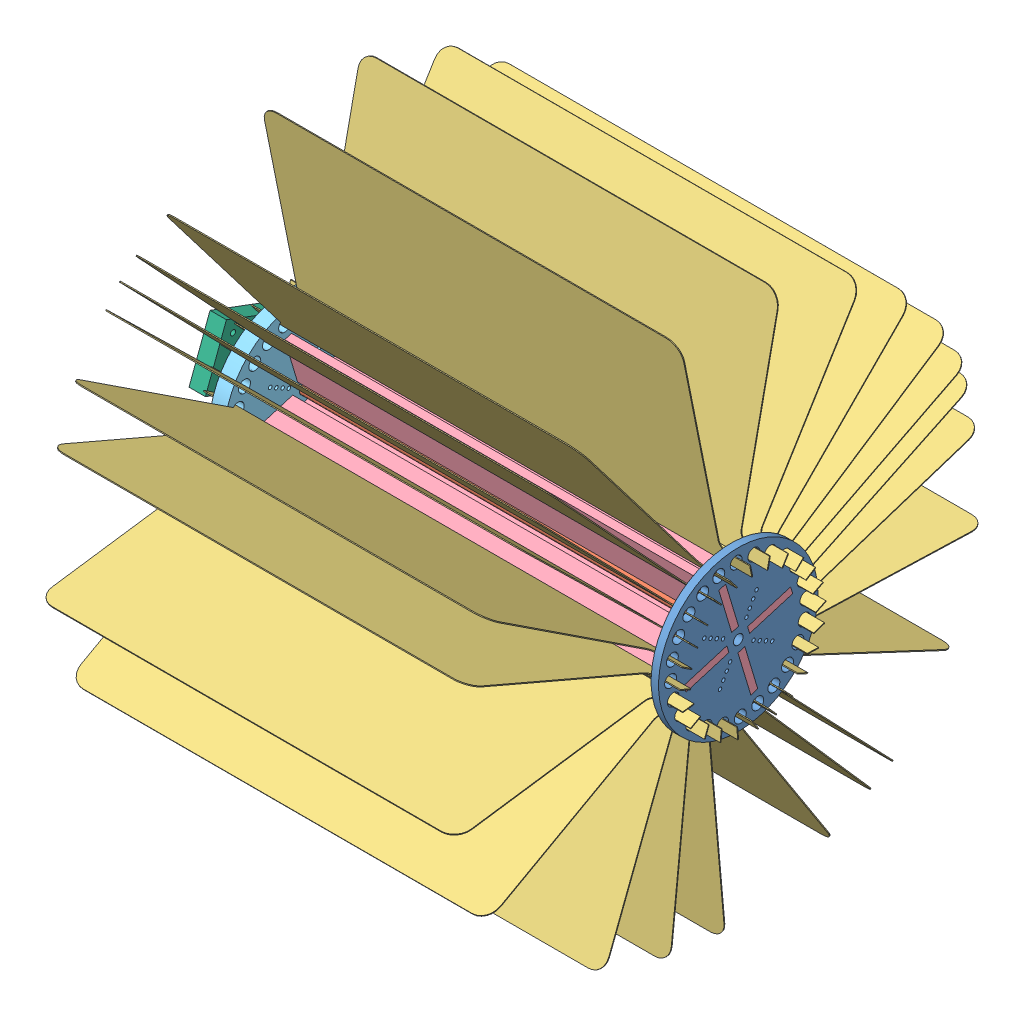
SolidWorks assembly FlipHubAssy_11_14_16, configuration Default. Lengths in mm.
32 component instances, 6 part files, 68 mates.
Components (placement in the parent):
- Hub_11_16_16v1-3: Hub_11_16_16v1 [Kerf Removed] at (92.075 0 0) x (0 0.287729 -0.957712) z (1 0 0) size (67.6 67.6 3.17)
- 4mmShaft-1: 4mmShaft [Default] at (-121.3698 0 0) x (0 0.397838 0.917456) z (1 0 0) size (4 4 201.85)
- flipcard-2: flipcard [Default] at (101.6 25.4911 6.9469) x (-1 0 0) z (0 -0.794345 -0.607467) size (203.2 0.36 88.9)
- flipcard-3: flipcard [Default] at (101.6 26.319 0.565) x (-1 0 0) z (0 -0.980438 -0.196828) size (203.2 0.36 88.9)
- flipcard-4: flipcard [Default] at (101.6 25.6398 -5.9296) x (-1 0 0) z (0 -0.978708 0.205258) size (203.2 0.36 88.9)
- flipcard-5: flipcard [Default] at (101.6 23.3418 -12.1967) x (-1 0 0) z (0 -0.851629 0.524146) size (203.2 0.36 88.9)
- flipcard-6: flipcard [Default] at (101.6 19.3329 -17.8702) x (-1 0 0) z (0 -0.709031 0.705178) size (203.2 0.36 88.9)
- flipcard-7: flipcard [Default] at (101.6 -22.5745 -13.5678) x (-1 0 0) z (0 0.72164 0.692269) size (203.2 0.36 88.9)
- flipcard-8: flipcard [Default] at (101.6 -25.5862 -6.8117) x (-1 0 0) z (0 0.750762 0.660573) size (203.2 0.36 88.9)
- flipcard-9: flipcard [Default] at (101.6 5.1297 26.0442) x (-1 0 0) z (0 -0.549176 -0.835707) size (203.2 0.36 88.9)
- flipcard-10: flipcard [Default] at (101.6 -26.5941 0.2889) x (-1 0 0) z (0 0.840236 0.542221) size (203.2 0.36 88.9)
- flipcard-11: flipcard [Default] at (101.6 -22.9237 13.1814) x (-1 0 0) z (0 0.994653 -0.103269) size (203.2 0.36 88.9)
- flipcard-12: flipcard [Default] at (101.6 -13.3499 -22.8996) x (-1 0 0) z (0 0.032698 0.999465) size (203.2 0.36 88.9)
- flipcard-13: flipcard [Default] at (101.6 -25.5459 6.6305) x (-1 0 0) z (0 0.996116 0.088049) size (203.2 0.36 88.9)
- flipcard-14: flipcard [Default] at (101.6 -18.5077 -18.8123) x (-1 0 0) z (0 0.425016 0.905186) size (203.2 0.36 88.9)
- flipcard-15: flipcard [Default] at (101.6 -7.1695 -25.6149) x (-1 0 0) z (0 -0.309308 0.950962) size (203.2 0.36 88.9)
- flipcard-16: flipcard [Default] at (101.6 -14.0926 22.2443) x (-1 0 0) z (0 0.484922 -0.874557) size (203.2 0.36 88.9)
- flipcard-17: flipcard [Default] at (101.6 -0.0085 -26.4638) x (-1 0 0) z (0 -0.43003 0.902814) size (203.2 0.36 88.9)
- flipcard-18: flipcard [Default] at (101.6 13.9305 -22.3267) x (-1 0 0) z (0 -0.549575 0.835444) size (203.2 0.36 88.9)
- flipcard-19: flipcard [Default] at (101.6 -18.7331 18.661) x (-1 0 0) z (0 0.933317 -0.359054) size (203.2 0.36 88.9)
- flipcard-20: flipcard [Default] at (101.6 7.3352 -25.2852) x (-1 0 0) z (0 -0.452884 0.891569) size (203.2 0.36 88.9)
- flipcard-21: flipcard [Default] at (101.6 -8.1039 25.1042) x (-1 0 0) z (0 0.139889 -0.990167) size (203.2 0.36 88.9)
- flipcard-22: flipcard [Default] at (101.6 11.8019 23.6999) x (-1 0 0) z (0 -0.698745 -0.715371) size (203.2 0.36 88.9)
- flipcard-23: flipcard [Default] at (101.6 17.8453 19.3621) x (-1 0 0) z (0 -0.716395 -0.697695) size (203.2 0.36 88.9)
- flipcard-24: flipcard [Default] at (101.6 -1.9741 26.5723) x (-1 0 0) z (0 -0.394871 -0.918737) size (203.2 0.36 88.9)
- flipcard-26: flipcard [Default] at (101.6 22.5539 13.593) x (-1 0 0) z (0 -0.730924 -0.682459) size (203.2 0.36 88.9)
- CenterSupport-2: CenterSupport [After Cut Kerf Removed] at (0 -4.8344 0.1389) x (1 0 0) z (0 0.287729 -0.957712) size (190.5 19.05 3.05)
- CenterSupport-3: CenterSupport [After Cut Kerf Removed] at (0 -0.1389 -4.8344) x (1 0 0) z (0 0.957712 0.287729) size (190.5 19.05 3.05)
- CenterSupport-4: CenterSupport [After Cut Kerf Removed] at (0 4.8344 -0.1389) x (1 0 0) z (0 -0.287729 0.957712) size (190.5 19.05 3.05)
- CenterSupport-5: CenterSupport [After Cut Kerf Removed] at (0 0.1389 4.8344) x (1 0 0) z (0 -0.957712 -0.287729) size (190.5 19.05 3.05)
- Hub_11_16_16v1-thicker-3: Hub_11_16_16v1-thicker [Kerf Removed] at (-95.25 0 0) x (0 0.957712 0.287729) z (1 0 0) size (67.6 72.68 6.35)
- bearingSleeve-nut-1: bearingSleeve-nut [Default] at (-119.7698 0 0) x (0 -0.936286 0.351239) z (-1 0 0) size (25.4 25.4 6.95)
Mates (geometry in assembly coordinates):
- Concentric2: concentric aligned: cylinder of Hub_11_16_16v1-3 through (95.25 0 0) axis (-1 0 0) radius 2.05; line of assembly
- Coincident4: coincident aligned: plane of flipcard-2; plane of assembly through (0 0 0) normal (1 0 0)
- Coincident5: coincident aligned: plane of flipcard-3; plane of assembly through (0 0 0) normal (1 0 0)
- Coincident6: coincident aligned: plane of flipcard-4; plane of assembly through (0 0 0) normal (1 0 0)
- Coincident7: coincident aligned: plane of flipcard-5; plane of assembly through (0 0 0) normal (1 0 0)
- Coincident8: coincident aligned: plane of flipcard-6; plane of assembly through (0 0 0) normal (1 0 0)
- Coincident9: coincident aligned: plane of flipcard-7; plane of assembly through (0 0 0) normal (1 0 0)
- Coincident10: coincident aligned: plane of flipcard-8; plane of assembly through (0 0 0) normal (1 0 0)
- Coincident11: coincident aligned: plane of flipcard-9; plane of assembly through (0 0 0) normal (1 0 0)
- Coincident12: coincident aligned: plane of flipcard-10; plane of assembly through (0 0 0) normal (1 0 0)
- Coincident13: coincident aligned: plane of flipcard-11; plane of assembly through (0 0 0) normal (1 0 0)
- Coincident14: coincident aligned: plane of flipcard-12; plane of assembly through (0 0 0) normal (1 0 0)
- Coincident15: coincident aligned: plane of flipcard-13; plane of assembly through (0 0 0) normal (1 0 0)
- Coincident16: coincident aligned: plane of flipcard-14; plane of assembly through (0 0 0) normal (1 0 0)
- Coincident17: coincident aligned: plane of flipcard-15; plane of assembly through (0 0 0) normal (1 0 0)
- Coincident18: coincident aligned: plane of flipcard-16; plane of assembly through (0 0 0) normal (1 0 0)
- Coincident19: coincident aligned: plane of flipcard-17; plane of assembly through (0 0 0) normal (1 0 0)
- Coincident20: coincident aligned: plane of flipcard-18; plane of assembly through (0 0 0) normal (1 0 0)
- Coincident21: coincident aligned: plane of flipcard-19; plane of assembly through (0 0 0) normal (1 0 0)
- Coincident22: coincident aligned: plane of flipcard-20; plane of assembly through (0 0 0) normal (1 0 0)
- Coincident23: coincident aligned: plane of flipcard-21; plane of assembly through (0 0 0) normal (1 0 0)
- Coincident24: coincident aligned: plane of flipcard-22; plane of assembly through (0 0 0) normal (1 0 0)
- Coincident25: coincident aligned: plane of flipcard-23; plane of assembly through (0 0 0) normal (1 0 0)
- Coincident26: coincident aligned: plane of flipcard-24; plane of assembly through (0 0 0) normal (1 0 0)
- Coincident28: coincident aligned: plane of flipcard-26; plane of assembly through (0 0 0) normal (1 0 0)
- Concentric5: concentric anti-aligned: cylinder of Hub_11_16_16v1-3 through (95.25 27.5055 8.2636) axis (-1 0 0) radius 2.54; line of flipcard-2 through (91.5988 27.5055 8.2636) axis (1 0 0)
- Concentric6: concentric anti-aligned: cylinder of Hub_11_16_16v1-3 through (95.25 28.707 0.8631) axis (-1 0 0) radius 2.54; line of flipcard-3 through (91.5988 28.707 0.8631) axis (1 0 0)
- Concentric7: concentric anti-aligned: cylinder of Hub_11_16_16v1-3 through (95.25 27.9522 -6.5963) axis (-1 0 0) radius 2.54; line of flipcard-4 through (91.5988 27.9522 -6.5963) axis (1 0 0)
- Concentric8: concentric anti-aligned: cylinder of Hub_11_16_16v1-3 through (95.25 25.2925 -13.6061) axis (-1 0 0) radius 2.54; line of flipcard-5 through (91.5988 25.2925 -13.6061) axis (1 0 0)
- Concentric9: concentric anti-aligned: cylinder of Hub_11_16_16v1-3 through (95.25 20.9092 -19.6887) axis (-1 0 0) radius 2.54; line of flipcard-6 through (91.5988 20.9092 -19.6887) axis (1 0 0)
- Concentric10: concentric anti-aligned: cylinder of Hub_11_16_16v1-3 through (95.25 15.1009 -24.4295) axis (-1 0 0) radius 2.54; line of flipcard-18 through (91.5988 15.1009 -24.4295) axis (1 0 0)
- Concentric11: concentric anti-aligned: cylinder of Hub_11_16_16v1-3 through (95.25 0.8631 -28.707) axis (-1 0 0) radius 2.54; line of flipcard-17 through (91.5988 0.8631 -28.707) axis (1 0 0)
- Concentric12: concentric anti-aligned: cylinder of Hub_11_16_16v1-3 through (95.25 -13.6061 -25.2925) axis (-1 0 0) radius 2.54; line of flipcard-12 through (91.5988 -13.6061 -25.2925) axis (1 0 0)
- Concentric13: concentric anti-aligned: cylinder of Hub_11_16_16v1-3 through (95.25 -6.5963 -27.9522) axis (-1 0 0) radius 2.54; line of flipcard-15 through (91.5988 -6.5963 -27.9522) axis (1 0 0)
- Concentric14: concentric anti-aligned: cylinder of Hub_11_16_16v1-3 through (95.25 8.2636 -27.5055) axis (-1 0 0) radius 2.54; line of flipcard-20 through (91.5988 8.2636 -27.5055) axis (1 0 0)
- Concentric15: concentric anti-aligned: cylinder of Hub_11_16_16v1-3 through (95.25 -19.6887 -20.9092) axis (-1 0 0) radius 2.54; line of flipcard-14 through (91.5988 -19.6887 -20.9092) axis (1 0 0)
- Concentric16: concentric anti-aligned: cylinder of Hub_11_16_16v1-3 through (95.25 -24.4295 -15.1009) axis (-1 0 0) radius 2.54; line of flipcard-7 through (91.5988 -24.4295 -15.1009) axis (1 0 0)
- Concentric17: concentric anti-aligned: cylinder of Hub_11_16_16v1-3 through (95.25 -27.5055 -8.2636) axis (-1 0 0) radius 2.54; line of flipcard-8 through (91.5988 -27.5055 -8.2636) axis (1 0 0)
- Concentric18: concentric anti-aligned: cylinder of Hub_11_16_16v1-3 through (95.25 -28.707 -0.8631) axis (-1 0 0) radius 2.54; line of flipcard-10 through (91.5988 -28.707 -0.8631) axis (1 0 0)
- Concentric19: concentric anti-aligned: cylinder of Hub_11_16_16v1-3 through (95.25 -27.9522 6.5963) axis (-1 0 0) radius 2.54; line of flipcard-13 through (91.5988 -27.9522 6.5963) axis (1 0 0)
- Concentric20: concentric anti-aligned: cylinder of Hub_11_16_16v1-3 through (95.25 -25.2925 13.6061) axis (-1 0 0) radius 2.54; line of flipcard-11 through (91.5988 -25.2925 13.6061) axis (1 0 0)
- Concentric21: concentric anti-aligned: cylinder of Hub_11_16_16v1-3 through (95.25 -20.9092 19.6887) axis (-1 0 0) radius 2.54; line of flipcard-19 through (91.5988 -20.9092 19.6887) axis (1 0 0)
- Concentric22: concentric anti-aligned: cylinder of Hub_11_16_16v1-3 through (95.25 -15.1009 24.4295) axis (-1 0 0) radius 2.54; line of flipcard-16 through (91.5988 -15.1009 24.4295) axis (1 0 0)
- Concentric23: concentric anti-aligned: cylinder of Hub_11_16_16v1-3 through (95.25 -8.2636 27.5055) axis (-1 0 0) radius 2.54; line of flipcard-21 through (91.5988 -8.2636 27.5055) axis (1 0 0)
- Concentric24: concentric anti-aligned: cylinder of Hub_11_16_16v1-3 through (95.25 -0.8631 28.707) axis (-1 0 0) radius 2.54; line of flipcard-24 through (91.5988 -0.8631 28.707) axis (1 0 0)
- Concentric25: concentric anti-aligned: cylinder of Hub_11_16_16v1-3 through (95.25 6.5963 27.9522) axis (-1 0 0) radius 2.54; line of flipcard-9 through (91.5988 6.5963 27.9522) axis (1 0 0)
- Concentric26: concentric anti-aligned: cylinder of Hub_11_16_16v1-3 through (95.25 13.6061 25.2925) axis (-1 0 0) radius 2.54; line of flipcard-22 through (91.5988 13.6061 25.2925) axis (1 0 0)
- Concentric27: concentric anti-aligned: cylinder of Hub_11_16_16v1-3 through (95.25 19.6887 20.9092) axis (-1 0 0) radius 2.54; line of flipcard-23 through (91.5988 19.6887 20.9092) axis (1 0 0)
- Concentric28: concentric anti-aligned: cylinder of Hub_11_16_16v1-3 through (95.25 24.4295 15.1009) axis (-1 0 0) radius 2.54; line of flipcard-26 through (91.5988 24.4295 15.1009) axis (1 0 0)
- Coincident31: coincident aligned: plane of CenterSupport-5; plane of assembly through (0 0 0) normal (1 0 0)
- Coincident32: coincident aligned: plane of CenterSupport-4; plane of assembly through (0 0 0) normal (1 0 0)
- Coincident33: coincident aligned: plane of CenterSupport-3; plane of assembly through (0 0 0) normal (1 0 0)
- Coincident34: coincident aligned: plane of CenterSupport-2; plane of assembly through (0 0 0) normal (1 0 0)
- Concentric29: concentric anti-aligned: cylinder of 4mmShaft-1 through (80.4802 0 0) axis (-1 0 0) radius 2; circle of Hub_11_16_16v1-thicker-3
- Coincident35: coincident aligned: plane of CenterSupport-5 through (-95.25 -8.2615 22.2018) normal (-1 0 0); plane of Hub_11_16_16v1-thicker-3 through (-95.25 0 0) normal (-1 0 0)
- Coincident36: coincident anti-aligned: plane of CenterSupport-5 through (0 -2.7802 3.9574) normal (0 -0.957712 -0.287729); plane of Hub_11_16_16v1-thicker-3 through (-88.9 -8.2615 22.2018) normal (0 0.957712 0.287729)
- Coincident37: coincident anti-aligned: plane of CenterSupport-5 through (-95.25 -8.2615 22.2018) normal (0 -0.287729 0.957712); plane of Hub_11_16_16v1-thicker-3 through (-88.9 -8.2615 22.2018) normal (0 0.287729 -0.957712)
- Coincident38: coincident anti-aligned: plane of CenterSupport-4 through (-95.25 22.2018 8.2615) normal (0 0.957712 0.287729); plane of Hub_11_16_16v1-thicker-3 through (-88.9 22.2018 8.2615) normal (0 -0.957712 -0.287729)
- Coincident39: coincident anti-aligned: plane of Hub_11_16_16v1-3 through (95.25 -5.3424 23.0788) normal (0 -0.957712 -0.287729); plane of CenterSupport-5 through (0 0.1389 4.8344) normal (0 0.957712 0.287729)
- Coincident40: coincident anti-aligned: plane of Hub_11_16_16v1-3 through (95.25 -2.7802 3.9574) normal (0 -0.287729 0.957712); plane of CenterSupport-5 through (-95.25 -2.7802 3.9574) normal (0 0.287729 -0.957712)
- Coincident41: coincident anti-aligned: plane of Hub_11_16_16v1-3 through (95.25 -22.2018 -8.2615) normal (0 -0.287729 0.957712); plane of CenterSupport-2 through (0 -3.9574 -2.7802) normal (0 0.287729 -0.957712)
- Coincident42: coincident anti-aligned: plane of Hub_11_16_16v1-3 through (95.25 8.2615 -22.2018) normal (0 -0.957712 -0.287729); plane of CenterSupport-3 through (0 2.7802 -3.9574) normal (0 0.957712 0.287729)
- Coincident43: coincident anti-aligned: plane of Hub_11_16_16v1-3 through (95.25 2.7802 -3.9574) normal (0 0.287729 -0.957712); plane of CenterSupport-3 through (-95.25 2.7802 -3.9574) normal (0 -0.287729 0.957712)
- Coincident44: coincident anti-aligned: plane of Hub_11_16_16v1-3 through (95.25 -3.9574 -2.7802) normal (0 -0.957712 -0.287729); plane of CenterSupport-2 through (-95.25 -3.9574 -2.7802) normal (0 0.957712 0.287729)
- Coincident45: coincident anti-aligned: plane of Hub_11_16_16v1-3 through (95.25 22.2018 8.2615) normal (0 0.287729 -0.957712); plane of CenterSupport-4 through (0 3.9574 2.7802) normal (0 -0.287729 0.957712)
- Coincident54: coincident aligned: plane of 4mmShaft-1 through (-121.3698 0 0) normal (-1 0 0); plane of bearingSleeve-nut-1 through (-121.3698 0 0) normal (-1 0 0)
- Concentric32: concentric aligned: cylinder of 4mmShaft-1 through (80.4802 0 0) axis (-1 0 0) radius 2; cylinder of bearingSleeve-nut-1 through (-119.7698 0 0) axis (-1 0 0) radius 4.45
- Coincident55: coincident aligned: plane of Hub_11_16_16v1-3 through (95.25 0 0) normal (1 0 0); plane of CenterSupport-3 through (95.25 8.2615 -22.2018) normal (1 0 0)
